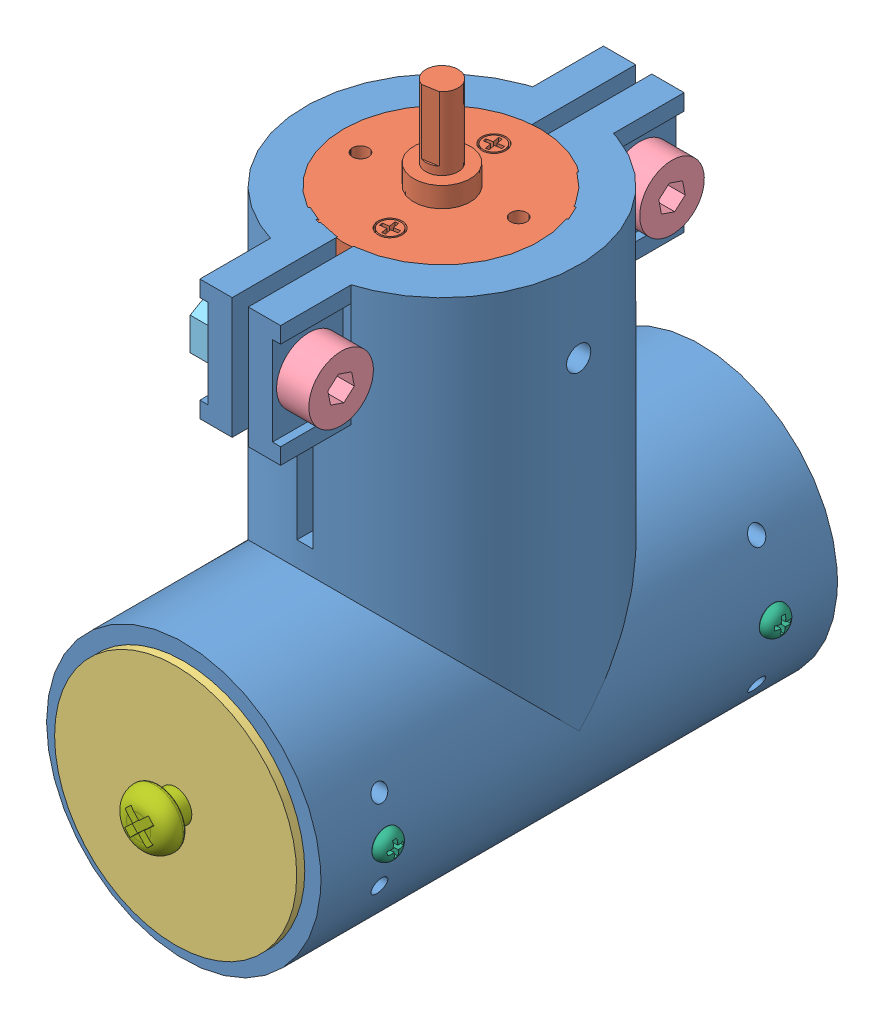
SolidWorks assembly motor_asm, configuration Default. Lengths in mm.
Overall size (36.76 78.5 75.37).
14 component instances, 7 part files, 22 mates.
Components (placement in the parent):
- motor_bracket-1: motor_bracket [Varsayılan] at (46.026 20.4793 21.0067) size (34 67 64)
- AL-GA25 - motor-1: AL-GA25 - motor [Varsayılan] at (-28.5347 23.1025 49.8721) x (-0.985905 0 0.167307) z (0 1 0) size (24.4 24.4 69.3)
- motor_case_cover-1: motor_case_cover [Varsayılan] at (29.5287 24.9025 86.0067) x (1 0 0) z (0 0 -1) size (30 30 16)
- motor_case_cover-2: motor_case_cover [Varsayılan] at (29.5287 24.9025 20.0067) size (30 30 16)
- m4_12mm_allen-1: m4_12mm_allen [Default] at (5.7289 67.4025 73.5067) x (0 -0.981506 -0.191429) z (0 -0.191429 0.981506) size (8 16 8)
- m4_12mm_allen-2: m4_12mm_allen [Default] at (5.7289 67.4025 32.5067) x (0 -0.981506 -0.191429) z (0 -0.191429 0.981506) size (8 16 8)
- m4_nut-1: m4_nut [Default] at (9.7289 67.4025 73.5067) x (0 1 0) z (0 0 1) size (8.08 3.2 7)
- m4_nut-2: m4_nut [Default] at (9.7289 67.4025 32.5067) x (0 1 0) z (0 0 1) size (8.08 3.2 7)
- m2_6mm_screw-1: m2_6mm_screw [Default] at (2.7289 24.9025 29.0067) x (0 -0.084036 -0.996463) z (0 0.996463 -0.084036) size (3.5 7.38 3.5)
- m2_6mm_screw-2: m2_6mm_screw [Default] at (24.7289 24.9025 29.0067) x (0 -0.084036 -0.996463) z (0 -0.996463 0.084036) size (3.5 7.38 3.5)
- m2_6mm_screw-3: m2_6mm_screw [Default] at (2.7289 24.9025 77.0067) x (0 -0.084036 0.996463) z (0 -0.996463 -0.084036) size (3.5 7.38 3.5)
- m2_6mm_screw-4: m2_6mm_screw [Default] at (24.7289 24.9025 77.0067) x (0 -0.084036 0.996463) z (0 0.996463 0.084036) size (3.5 7.38 3.5)
- m4_18mm_screw-1: m4_18mm_screw [Default] at (13.7289 24.9025 36.0067) x (0.678877 -0.734252 0) z (0.734252 0.678877 0) size (7 20.68 7)
- m4_18mm_screw-2: m4_18mm_screw [Default] at (13.7289 24.9025 70.0067) x (0.678877 -0.734252 0) z (-0.734252 -0.678877 0) size (7 20.68 7)
Mates (geometry in assembly coordinates):
- Concentric1: concentric: cylinder of motor_bracket-1 through (13.7289 74.9025 53.0067) axis (0 -1 0) radius 12; cylinder of AL-GA25 - motor-1 through (13.7289 74.9025 53.0067) axis (0 -1 0) radius 12.2
- Coincident1: coincident: plane of motor_bracket-1 through (13.7289 74.9025 53.0067) normal (0 1 0); plane of AL-GA25 - motor-1 through (13.7289 74.9025 53.0067) normal (0 1 0)
- Concentric2: concentric: cylinder of motor_bracket-1 through (13.7289 24.9025 85.0067) axis (0 0 -1) radius 12; cylinder of motor_case_cover-1 through (13.7289 24.9025 70.0067) axis (0 0 1) radius 11.118
- Coincident2: coincident: plane of motor_bracket-1 through (13.7289 24.9025 85.0067) normal (0 0 1); plane of motor_case_cover-1 through (13.7289 24.9025 85.0067) normal (0 0 -1)
- Concentric3: concentric: cylinder of motor_bracket-1 through (13.7289 24.9025 85.0067) axis (0 0 -1) radius 12; cylinder of motor_case_cover-2 through (13.7289 24.9025 36.0067) axis (0 0 -1) radius 11.118
- Coincident3: coincident: plane of motor_bracket-1 through (13.7289 24.9025 21.0067) normal (0 0 -1); plane of motor_case_cover-2 through (13.7289 24.9025 21.0067) normal (0 0 1)
- Concentric4: concentric: cylinder of motor_bracket-1 through (-3.2711 67.4025 73.5067) axis (1 0 0) radius 2; cylinder of m4_12mm_allen-1 through (17.7289 67.4025 73.5067) axis (-1 0 0) radius 2
- Coincident4: coincident: plane of motor_bracket-1 through (17.7289 20.4793 21.0067) normal (1 0 0); plane of m4_12mm_allen-1 through (17.7289 67.4025 73.5067) normal (-1 0 0)
- Concentric5: concentric: cylinder of motor_bracket-1 through (-3.2711 67.4025 32.5067) axis (1 0 0) radius 2; cylinder of m4_12mm_allen-2 through (17.7289 67.4025 32.5067) axis (-1 0 0) radius 2
- Coincident5: coincident: plane of motor_bracket-1 through (17.7289 20.4793 21.0067) normal (1 0 0); plane of m4_12mm_allen-2 through (17.7289 67.4025 32.5067) normal (-1 0 0)
- Concentric6: concentric: cylinder of m4_12mm_allen-1 through (17.7289 67.4025 73.5067) axis (-1 0 0) radius 2; cylinder of m4_nut-1 through (6.5289 67.4025 73.5067) axis (1 0 0) radius 2
- Concentric7: concentric: cylinder of m4_12mm_allen-2 through (17.7289 67.4025 32.5067) axis (-1 0 0) radius 2; cylinder of m4_nut-2 through (6.5289 67.4025 32.5067) axis (1 0 0) radius 2
- Coincident7: coincident: plane of motor_bracket-1 through (9.7289 20.4793 21.0067) normal (-1 0 0); plane of m4_nut-2 through (9.7289 67.4025 32.5067) normal (1 0 0)
- Parallel1: parallel: plane of motor_bracket-1 through (9.7289 69.4954 36.1317) normal (0 -0.866025 -0.5); plane of m4_nut-2 through (6.5289 69.4232 36.0067) normal (0 0.866025 0.5)
- Coincident10: coincident: plane of motor_bracket-1 through (9.7289 20.4793 21.0067) normal (-1 0 0); plane of m4_nut-1 through (9.7289 67.4025 73.5067) normal (1 0 0)
- Parallel3: parallel: plane of motor_bracket-1 through (9.7289 64.226 75.2548) normal (0 0.866025 -0.5); plane of m4_nut-1 through (6.5289 63.3611 73.5067) normal (0 -0.866025 0.5)
- Concentric8: concentric: cylinder of motor_bracket-1 through (-3.2711 24.9025 77.0067) axis (1 0 0) radius 1; cylinder of motor_case_cover-1 through (-1.2711 24.9025 77.0067) axis (1 0 0) radius 1
- Concentric9: concentric: cylinder of motor_bracket-1 through (-3.2711 24.9025 29.0067) axis (1 0 0) radius 1; cylinder of motor_case_cover-2 through (-1.2711 24.9025 29.0067) axis (1 0 0) radius 1
- Concentric11: concentric: cylinder of motor_bracket-1 through (-3.2711 24.9025 29.0067) axis (1 0 0) radius 1; cylinder of m2_6mm_screw-1 through (-3.2711 24.9025 29.0067) axis (1 0 0) radius 1
- Tangent1: tangent: cylinder of motor_bracket-1 through (13.7289 24.9025 85.0067) axis (0 0 -1) radius 17; plane of m2_6mm_screw-1 through (-3.2711 24.9025 29.0067) normal (1 0 0)
- Concentric12: concentric: cylinder of motor_case_cover-2 through (13.7289 24.9025 20.0067) axis (0 0 1) radius 2; cylinder of m4_18mm_screw-1 through (13.7289 24.9025 17.0067) axis (0 0 1) radius 2
- Distance1: distance = 2 mm: plane of m4_18mm_screw-1 through (13.7289 24.9025 18.0067) normal (0 0 1); plane of motor_case_cover-2 through (13.7289 24.9025 20.0067) normal (0 0 -1)
